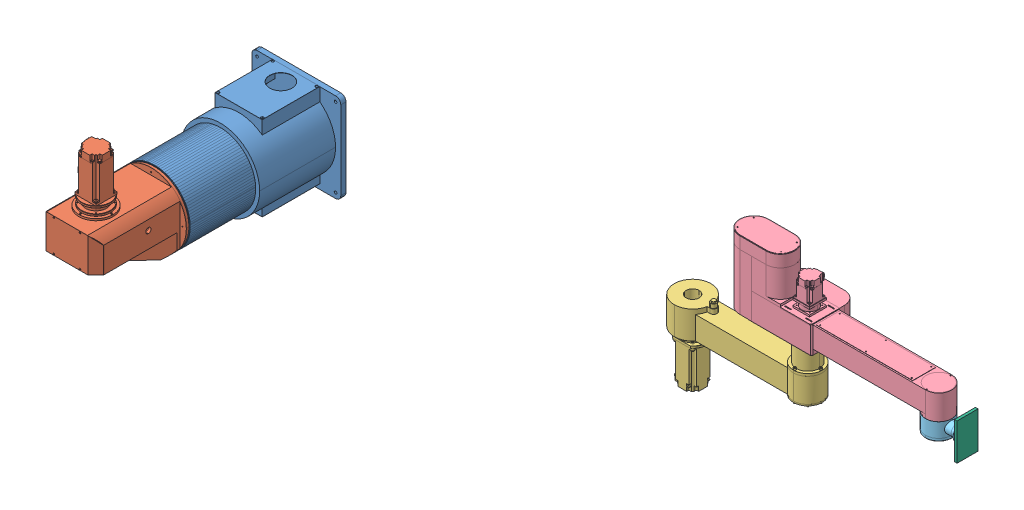
SolidWorks assembly robot, configuration Default. Lengths in mm.
Overall size (2477.07 663.3 1259.53).
6 component instances, 6 part files, 14 mates.
Components (placement in the parent):
- K0.step-1: K0.step [Default] at (210.3787 713.4922 228.9829) x (1 0 0) z (0 -1 0) size (340 563 343.75)
- K1.step-1: K1.step [Default] at (-1.469 967.4466 888.8194) x (0 0 -1) z (0 -1 0) size (334.65 270 444)
- K2.step-1: K2.step [Default] at (1113.1645 -252.6982 -117.4998) x (0 0 1) z (0 1 0) size (140 568 370.3)
- K3.step-1: K3.step [Default] at (1554.6961 884.8171 -410.1714) x (1 0 0) z (0 -1 0) size (810 181.77 283)
- K4.step-1: K4.step [Default] at (2266.2552 301.0815 54.2537) x (0 0 -1) z (-1 0 0) size (100 67.5 145)
- K5.step-1: K5.step [Default] at (2290.1259 277.5438 39.6443) x (-1 0 0) z (0 -1 0) size (15 80 140)
Mates (geometry in assembly coordinates):
- Concentric1: concentric anti-aligned: circle of K0.step-1; circle of K1.step-1
- Coincident1: coincident anti-aligned: plane of K0.step-1 through (-16.9437 283.0438 839.523) normal (0 0 1); plane of K1.step-1 through (-16.9437 283.0438 839.523) normal (0 0 -1)
- Parallel4: parallel aligned: plane of K0.step-1 through (-16.9437 132.0438 406.523) normal (0 -1 0); plane of K1.step-1 through (-126.9437 263.0438 851.523) normal (0 -1 0)
- Coincident6: coincident anti-aligned: plane of K1.step-1 through (-16.9437 222.0438 1061.523) normal (0 -1 0); plane of K2.step-1 through (1240.1259 222.0438 39.6443) normal (0 1 0)
- Concentric3: concentric anti-aligned: circle of K2.step-1; circle of K3.step-1
- Coincident8: coincident anti-aligned: plane of K2.step-1 through (1680.1259 299.0438 39.6443) normal (0 1 0); plane of K3.step-1 through (1629.1259 299.0438 67.1443) normal (0 -1 0)
- Parallel5: parallel aligned: plane of K1.step-1 through (63.0563 393.0438 1172.523) normal (0 0 1); plane of K2.step-1 through (1240.1259 204.0438 83.6443) normal (0 0 1)
- Parallel6: parallel aligned: plane of K2.step-1 through (1240.1259 204.0438 83.6443) normal (0 0 1); plane of K3.step-1 through (1750.1259 320.0438 89.6443) normal (0 0 1)
- Concentric4: concentric anti-aligned: circle of K3.step-1; circle of K4.step-1
- Coincident11: coincident anti-aligned: plane of K3.step-1 through (2180.1259 305.0438 39.6443) normal (0 -1 0); plane of K4.step-1 through (2180.1259 305.0438 39.6443) normal (0 1 0)
- Parallel7: parallel aligned: plane of K1.step-1 through (93.0563 263.0438 851.523) normal (1 0 0); plane of K4.step-1 through (2275.1259 277.5438 39.6443) normal (1 0 0)
- Coincident13: coincident anti-aligned: plane of K4.step-1 through (2275.1259 277.5438 39.6443) normal (1 0 0); plane of K5.step-1 through (2275.1259 277.5438 39.6443) normal (-1 0 0)
- Coincident14: coincident aligned: circle of K4.step-1; circle of K5.step-1
- Parallel8: parallel aligned: plane of K3.step-1 through (1750.1259 320.0438 89.6443) normal (0 0 1); plane of K5.step-1 through (2280.1259 347.5438 79.6443) normal (0 0 1)
